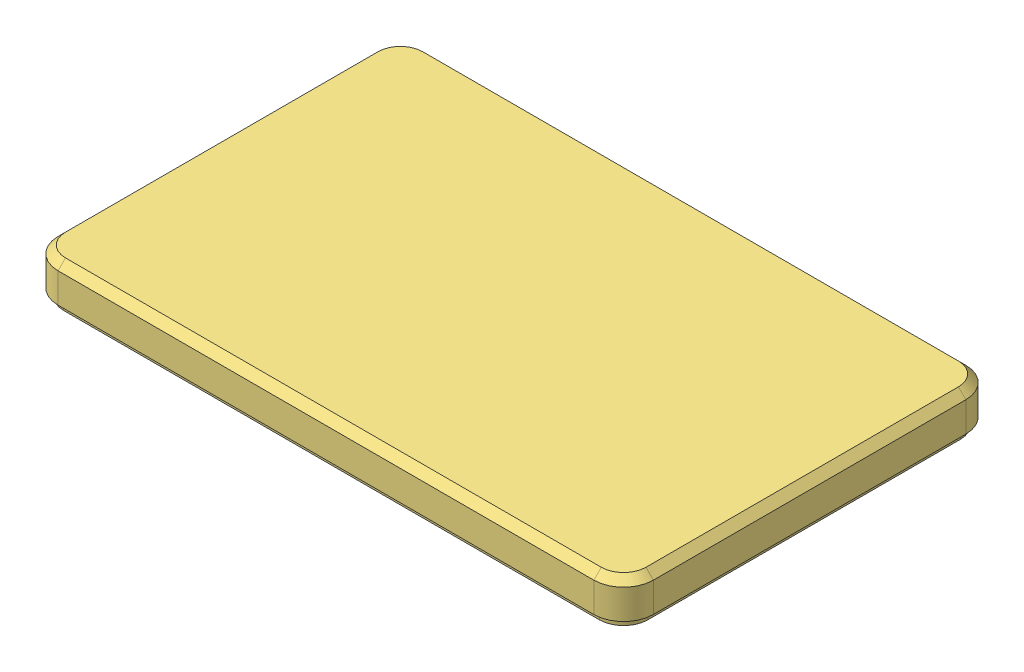
SolidWorks assembly 6 Panel, configuration Domyślna. Lengths in mm.
Overall size (160 15.2 100).
6 component instances, 6 part files, 17 mates.
Components (placement in the parent):
- Część3^6 Panel-1: Część3^6 Panel [Domyślna] at origin size (160 35 100) (hidden, virtual)
- 1.2.6 screen-1: 1.2.6 screen [Domyślna] at (-13.85 38.3 -21.2) size (77.5 14.2 42.8)
- 1.2.5.2 nucleo-f411re-1: 1.2.5.2 nucleo-f411re [Domyślna] at (22.4193 12.9 4.3019) size (82.5 19 70) (hidden)
- 1.2.8 buttons-1: 1.2.8 buttons [Domyślna] at (-14.6 33 18.4) size (76 7.6 17.4)
- 1.2.10 SP21-1: 1.2.10 SP21 [Domyślna] at (-55 19.4971 -47.6) x (-1 0 0) z (0 0 -1) size (32.33 29 27) (hidden)
- Część1^6 Panel-1: Część1^6 Panel [Domyślna] at (0 35 0) x (1 0 0) z (0 1 0) size (160 100 12) (virtual)
Mates (geometry in assembly coordinates):
- Wspólnie1: coordinate: point of Część3^6 Panel-1; point of assembly
- Wspólnie2: coincident anti-aligned: plane of Część3^6 Panel-1 through (0 29.1971 -50) normal (0 -1 0); plane of 1.2.10 SP21-1 through (-50.98 29.1971 -50) normal (0 1 0)
- Koncentryczne1: concentric aligned: cylinder of Część3^6 Panel-1 through (-55 19.4971 -50) axis (0 0 1) radius 10.5; cylinder of 1.2.10 SP21-1 through (-55 19.4971 -50) axis (0 0 1) radius 10.5
- Wspólnie3: coincident anti-aligned: plane of Część3^6 Panel-1 through (-72 35 -50) normal (0 0 -1); plane of 1.2.10 SP21-1 through (-55 19.4971 -50) normal (0 0 1)
- Odległość1: distance = 16 mm anti-aligned: plane of 1.2.5.2 nucleo-f411re-1 through (61.6 14.9 4.3019) normal (1 0 0); plane of Część3^6 Panel-1 through (77.6 35 42) normal (-1 0 0)
- Szerokość1: width anti-aligned: plane of Część3^6 Panel-1 through (-72 35 -47.6) normal (0 0 1); plane of Część3^6 Panel-1 through (-72 35 47.6) normal (0 0 -1); plane of 1.2.5.2 nucleo-f411re-1 through (22.4193 14.9 -35) normal (0 0 -1); plane of 1.2.5.2 nucleo-f411re-1 through (22.4193 14.9 35) normal (0 0 1)
- Odległość2: distance = 2 mm anti-aligned: plane of Część3^6 Panel-1 through (72 2.4 -42) normal (0 1 0); plane of 1.2.5.2 nucleo-f411re-1 through (22.4193 4.4 4.3019) normal (0 -1 0)
- Ustalone1: in place: plane of Część3^6 Panel-1 through (72 35 -42) normal (0 1 0); plane of Część1^6 Panel-1 through (0 35 0) normal (0 1 0); moOrthogonalPlaneRef_w of Część3^6 Panel-1 through (72 35 -42) normal (0 1 0); plane of Część1^6 Panel-1 through (0 35 0) normal (0 0 -1); plane of Część3^6 Panel-1 through (72 35 -42) normal (0 1 0); plane of Część1^6 Panel-1 through (0 35 0) normal (1 0 0); plane of Część3^6 Panel-1 through (72 35 -42) normal (0 1 0); unknown of Część1^6 Panel-1
- Wspólnie4: coincident aligned: plane of Część3^6 Panel-1; plane of Część1^6 Panel-1
- Wspólnie5: coincident aligned: moOrthogonalPlaneRef_w of Część3^6 Panel-1 through (0 35 0) normal (0 0 -1); plane of Część1^6 Panel-1 through (0 35 0) normal (0 0 -1)
- Wspólnie6: coincident anti-aligned: moOrthogonalPlaneRef_w of Część3^6 Panel-1 through (0 35 0) normal (-1 0 0); plane of Część1^6 Panel-1 through (0 35 0) normal (1 0 0)
- Odległość3: distance = 4 mm anti-aligned: plane of 1.2.8 buttons-1 through (17.9 38.6 22) normal (0 1 0); plane of Część1^6 Panel-1 through (-72 42.6 42) normal (0 -1 0)
- Odległość4: distance = 1 mm aligned: plane of 1.2.6 screen-1 through (-13.85 44 -21.2) normal (0 1 0); plane of Część1^6 Panel-1 through (-72 45 42) normal (0 1 0)
- Odległość5: distance = 5 mm anti-aligned: plane of 1.2.6 screen-1 through (-52.6 40 -42.6) normal (0 0 -1); plane of Część1^6 Panel-1 through (-72 45 -47.6) normal (0 0 1)
- Odległość6: distance = 25 mm anti-aligned: plane of 1.2.6 screen-1 through (-52.6 40 0.2) normal (-1 0 0); plane of Część1^6 Panel-1 through (-77.6 45 42) normal (1 0 0)
- Wspólnie11: coincident aligned: plane of 1.2.6 screen-1 through (-52.6 40 0.2) normal (-1 0 0); plane of 1.2.8 buttons-1 through (-52.6 34.6 26.6) normal (-1 0 0)
- Odległość7: distance = 10 mm anti-aligned: plane of 1.2.8 buttons-1 through (-52.6 34.6 10.2) normal (0 0 -1); plane of 1.2.6 screen-1 through (-52.6 40 0.2) normal (0 0 1)
